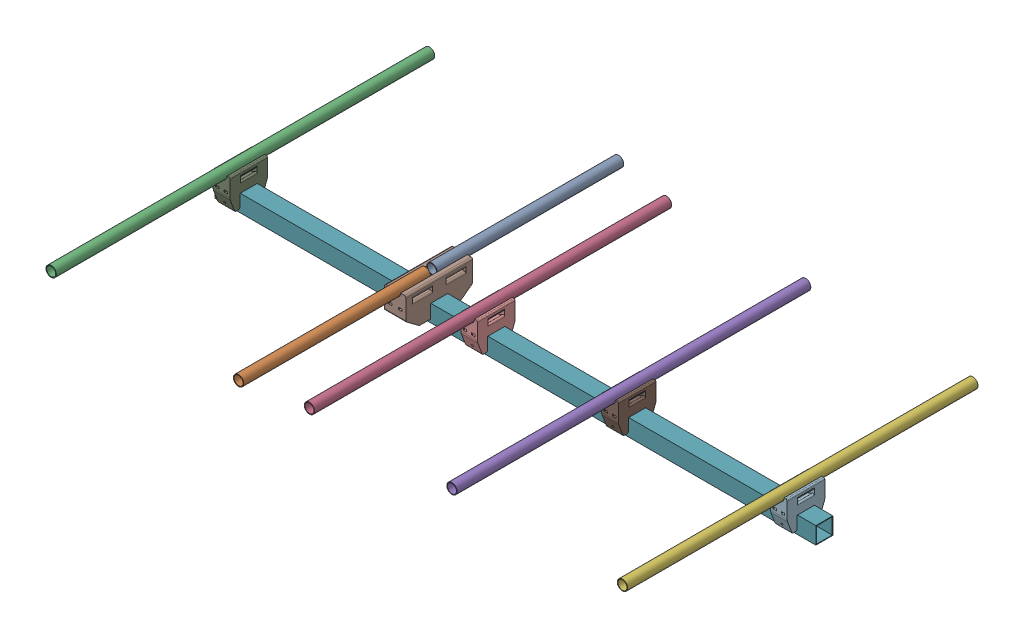
SolidWorks assembly FLTSATCOM-Yagi-Uda, configuration Default. Lengths in mm.
Overall size (900 60.9 569.4).
12 component instances, 9 part files, 9 mates.
Components (placement in the parent):
- Dipole-B-1: Dipole-B [Default] at origin size (15.5 15.5 279.7)
- Dipole-A-1: Dipole-A [Default] at origin size (15.5 15.5 279.7)
- Reflector Geometry-1: Reflector Geometry [Default] at origin size (15.5 15.5 567)
- Director Geometry #1-1: Director Geometry #1 [Default] at origin size (15.5 15.5 535)
- Director Geometry #2-1: Director Geometry #2 [Default] at origin size (15.5 15.5 530)
- Director Geometry #3-1: Director Geometry #3 [Default] at origin size (15.5 15.5 525)
- Antenna Beam-1: Antenna Beam [Default] at origin size (900 25.4 25.4)
- Dipole Base-1: Dipole Base [Default] at origin size (32 48.15 100)
- Director Base-1: Director Base [Default] at origin size (25 47.75 56.4)
- Director Base-2: Director Base [Default] at (371 0 0) size (25 47.75 56.4)
- Director Base-3: Director Base [Default] at (582 0 0) size (25 47.75 56.4)
- Director Base-4: Director Base [Default] at (835 0 0) size (25 47.75 56.4)
Mates (geometry in assembly coordinates):
- Coincident1: coincident aligned: plane of Director Base-1 through (-425 40.45 28.2) normal (0 0 1); plane of Director Base-2 through (-54 40.45 28.2) normal (0 0 1)
- Coincident2: coincident aligned: plane of Director Base-1 through (450 40.45 -28.2) normal (0 1 0); plane of Director Base-2 through (821 40.45 -28.2) normal (0 1 0)
- Coincident3: coincident aligned: plane of Director Base-1 through (450 40.45 -28.2) normal (0 1 0); plane of Director Base-3 through (1032 40.45 -28.2) normal (0 1 0)
- Coincident4: coincident aligned: plane of Director Base-1 through (-425 40.45 28.2) normal (0 0 1); plane of Director Base-3 through (157 40.45 28.2) normal (0 0 1)
- Coincident5: coincident aligned: plane of Director Base-1 through (-425 40.45 28.2) normal (0 0 1); plane of Director Base-4 through (410 40.45 28.2) normal (0 0 1)
- Coincident6: coincident aligned: plane of Director Base-1 through (450 40.45 -28.2) normal (0 1 0); plane of Director Base-4 through (1285 40.45 -28.2) normal (0 1 0)
- Concentric1: concentric anti-aligned: cylinder of Director Geometry #1-1 through (-54 40.45 267.5) axis (0 0 -1) radius 7.75; cylinder of Director Base-2 through (-54 40.45 -28.2) axis (0 0 1) radius 8
- Concentric2: concentric anti-aligned: cylinder of Director Geometry #2-1 through (157 40.45 265) axis (0 0 -1) radius 7.75; cylinder of Director Base-3 through (157 40.45 -28.2) axis (0 0 1) radius 8
- Concentric3: concentric anti-aligned: cylinder of Director Geometry #3-1 through (410 40.45 262.5) axis (0 0 -1) radius 7.75; cylinder of Director Base-4 through (410 40.45 -28.2) axis (0 0 1) radius 8
